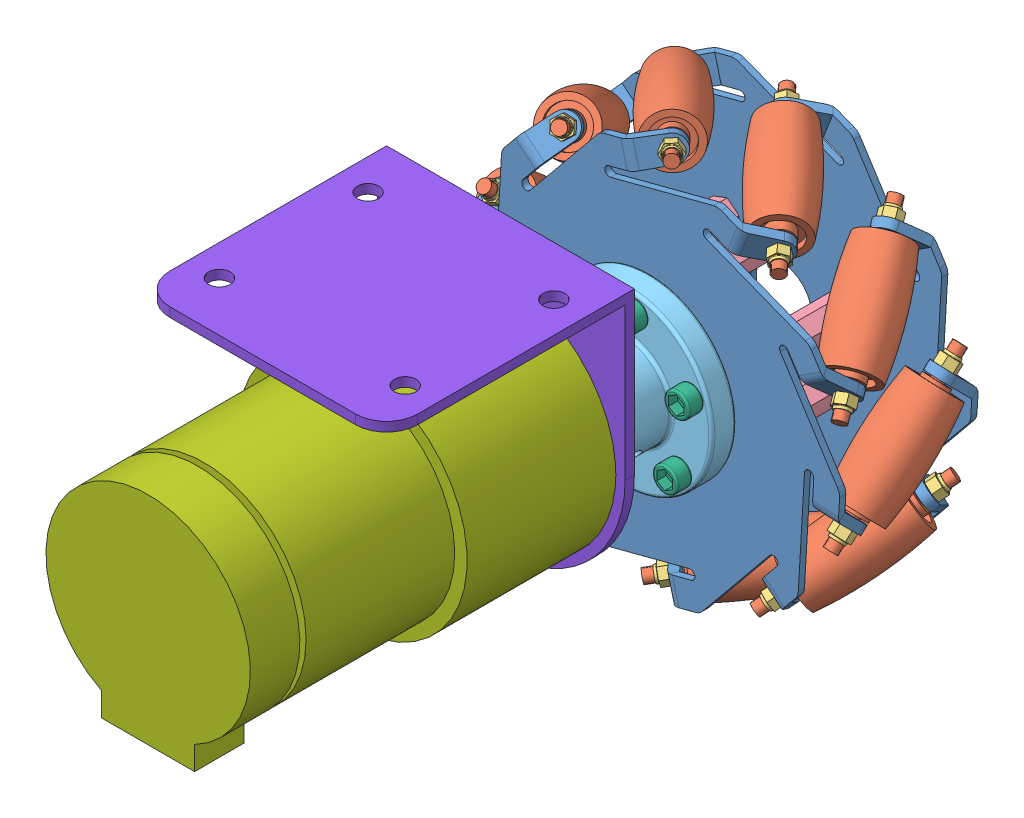
SolidWorks assembly 右后轮, configuration 默认. Lengths in mm.
Overall size (90.68 90.68 106.57).
61 component instances, 8 part files, 16 mates.
Components (placement in the parent):
- 麦克纳姆轮装配（2）-1: 麦克纳姆轮装配（2） [默认] at (-61.9802 -80.9379 78.6914) x (-0.633859 -0.773449 0) z (0 0 1) size (73.19 68.37 28.98)
  - 麦克纳姆轮（2）-1: 麦克纳姆轮（2） [默认] at (4.7846 1.1432 62.959) size (62.96 61.4 5.95)
  - 麦克纳姆轮（2）-2: 麦克纳姆轮（2） [默认] at (4.7846 1.1432 85.0986) x (-1 0 0) z (0 0 -1) size (62.96 61.4 5.95)
  - 辊子-1: 辊子 [默认] at (-6.5323 29.7426 62.712) x (0.707107 0 0.707107) z (-0.707107 0 0.707107) size (28 9.23 9.23)
  - 辊子-2: 辊子 [默认] at (-21.1917 17.6211 62.6991) x (0.572061 0.415627 0.707107) z (-0.707107 -0.186947 0.681946) size (28 9.23 9.23)
  - 辊子-3: 辊子 [默认] at (-25.9161 -0.7943 62.6991) x (0.218508 0.672499 0.707107) z (-0.650722 -0.439573 0.619142) size (28 9.23 9.23)
  - 辊子-4: 辊子 [默认] at (-25.9121 3.0685 85.3457) x (0.218508 -0.672499 -0.707107) z (0.395342 -0.60148 0.694209) size (28 9.23 9.23)
  - 辊子-6: 辊子 [默认] at (-21.1812 -15.3423 85.3457) x (0.572061 -0.415627 -0.707107) z (0.647393 -0.300533 0.700401) size (28 9.23 9.23)
  - 辊子-7: 辊子 [默认] at (-6.5323 -27.4561 85.3457) x (0.707107 0 -0.707107) z (0.705301 0.071414 0.705301) size (28 9.23 9.23)
  - 辊子-8: 辊子 [默认] at (12.4393 -28.646 85.3457) x (0.572061 0.415627 -0.707107) z (0.714443 0.170963 0.678486) size (28 9.23 9.23)
  - 辊子-9: 辊子 [默认] at (35.4853 3.0808 62.6991) x (-0.218508 -0.672499 0.707107) z (-0.954109 -0.00482 -0.29942) size (28 9.23 9.23)
  - 辊子-10: 辊子 [默认] at (28.4831 20.7562 62.6991) x (0.218508 -0.672499 0.707107) z (-0.771684 0.324444 0.547028) size (28 9.23 9.23)
  - 辊子-11: 辊子 [默认] at (12.4289 30.9401 62.6991) x (0.572061 -0.415627 0.707107) z (-0.689 0.22422 0.689206) size (28 9.23 9.23)
  - M2【螺母】-1: M2【螺母】 [默认] at (-5.0722 29.3326 82.6238) x (0.808299 -0.139279 -0.572061) z (-0.572061 -0.415627 -0.707107) size (2.79 3.22 1.95)
  - M2【螺母】-2: M2【螺母】 [默认] at (13.3795 29.7426 82.6238) x (0.572061 -0.587785 -0.572061) z (-0.707107 0 -0.707107) size (2.79 3.22 1.95)
  - M2【螺母】-3: M2【螺母】 [默认] at (28.5483 19.2286 82.6238) x (0.117316 -0.811778 -0.572061) z (-0.572061 0.415627 -0.707107) size (2.79 3.22 1.95)
  - M2【螺母】-4: M2【螺母】 [默认] at (34.6402 1.8066 82.6238) x (-0.38224 -0.725698 -0.572061) z (-0.218508 0.672499 -0.707107) size (2.79 3.22 1.95)
  - M2【螺母】-5: M2【螺母】 [默认] at (29.3282 -15.8687 82.6238) x (-0.735794 -0.362427 -0.572061) z (0.218508 0.672499 -0.707107) size (2.79 3.22 1.95)
  - M2【螺母】-6: M2【螺母】 [默认] at (14.6414 -27.0461 82.6238) x (-0.808299 0.139279 -0.572061) z (0.572061 0.415627 -0.707107) size (2.79 3.22 1.95)
  - M2【螺母】-7: M2【螺母】 [默认] at (-3.8104 -27.4561 82.6238) x (-0.572061 0.587785 -0.572061) z (0.707107 0 -0.707107) size (2.79 3.22 1.95)
  - M2【螺母】-8: M2【螺母】 [默认] at (-18.9791 -16.9422 82.6238) x (-0.117316 0.811778 -0.572061) z (0.572061 -0.415627 -0.707107) size (2.79 3.22 1.95)
  - M2【螺母】-9: M2【螺母】 [默认] at (-25.071 0.4798 82.6238) x (0.38224 0.725698 -0.572061) z (0.218508 -0.672499 -0.707107) size (2.79 3.22 1.95)
  - M2【螺母】-10: M2【螺母】 [默认] at (-19.759 18.1552 82.6238) x (0.735794 0.362427 -0.572061) z (-0.218508 -0.672499 -0.707107) size (2.79 3.22 1.95)
  - M2【螺母】-11: M2【螺母】 [默认] at (-19.759 -15.8687 65.4339) x (0.972031 0.086079 0.218508) z (-0.218508 0.672499 0.707107) size (2.79 3.22 1.95)
  - M2【螺母】-12: M2【螺母】 [默认] at (-5.0722 -27.0461 65.4339) x (0.735794 0.640985 0.218508) z (-0.572061 0.415627 0.707107) size (2.79 3.22 1.95)
  - M2【螺母】-13: M2【螺母】 [默认] at (13.3795 -27.4561 65.4339) x (0.218508 0.951057 0.218508) z (-0.707107 0 0.707107) size (2.79 3.22 1.95)
  - M2【螺母】-14: M2【螺母】 [默认] at (28.5483 -16.9422 65.4339) x (-0.38224 0.897857 0.218508) z (-0.572061 -0.415627 0.707107) size (2.79 3.22 1.95)
  - M2【螺母】-15: M2【螺母】 [默认] at (34.6402 0.4798 65.4339) x (-0.836986 0.501706 0.218508) z (-0.218508 -0.672499 0.707107) size (2.79 3.22 1.95)
  - M2【螺母】-16: M2【螺母】 [默认] at (29.3282 18.1552 65.4339) x (-0.972031 -0.086079 0.218508) z (0.218508 -0.672499 0.707107) size (2.79 3.22 1.95)
  - M2【螺母】-17: M2【螺母】 [默认] at (14.6414 29.3326 65.4339) x (-0.735794 -0.640985 0.218508) z (0.572061 -0.415627 0.707107) size (2.79 3.22 1.95)
  - M2【螺母】-18: M2【螺母】 [默认] at (-3.8104 29.7426 65.4339) x (-0.218508 -0.951057 0.218508) z (0.707107 0 0.707107) size (2.79 3.22 1.95)
  - M2【螺母】-19: M2【螺母】 [默认] at (-18.9791 19.2286 65.4339) x (0.38224 -0.897857 0.218508) z (0.572061 0.415627 0.707107) size (2.79 3.22 1.95)
  - M2【螺母】-20: M2【螺母】 [默认] at (-25.071 1.8066 65.4339) x (0.836986 -0.501706 0.218508) z (0.218508 0.672499 0.707107) size (2.79 3.22 1.95)
  - 20mm长-M3【六角铜柱】-1: 20mm长-M3【六角铜柱】 [默认] at (14.7439 -4.6068 64.0986) size (4.27 4.93 20)
  - 20mm长-M3【六角铜柱】-2: 20mm长-M3【六角铜柱】 [默认] at (4.7846 -10.3568 64.0986) x (0.5 -0.866025 0) z (0 0 1) size (4.27 4.93 20)
  - 20mm长-M3【六角铜柱】-3: 20mm长-M3【六角铜柱】 [默认] at (-5.1747 -4.6068 64.0986) x (-0.5 -0.866025 0) z (0 0 1) size (4.27 4.93 20)
  - 20mm长-M3【六角铜柱】-4: 20mm长-M3【六角铜柱】 [默认] at (-5.1747 6.8932 64.0986) x (-1 0 0) z (0 0 1) size (4.27 4.93 20)
  - 20mm长-M3【六角铜柱】-5: 20mm长-M3【六角铜柱】 [默认] at (4.7846 12.6432 64.0986) x (-0.5 0.866025 0) z (0 0 1) size (4.27 4.93 20)
  - 20mm长-M3【六角铜柱】-6: 20mm长-M3【六角铜柱】 [默认] at (14.7439 6.8932 64.0986) x (0.5 0.866025 0) z (0 0 1) size (4.27 4.93 20)
- 法兰联轴器-1: 法兰联轴器 [默认] at (-64.1287 -85.3632 163.79) x (-0.633859 -0.773449 0) z (0 0 1) size (28 28 16)
- M3-8【内六角螺丝】-1: M3-8【内六角螺丝】 [默认] at (-55.2341 -92.6526 159.79) size (4 4 10.5)
- M3-8【内六角螺丝】-2: M3-8【内六角螺丝】 [默认] at (-53.3686 -81.3049 159.79) x (0.5 0.866025 0) z (0 0 1) size (4 4 10.5)
- M3-8【内六角螺丝】-3: M3-8【内六角螺丝】 [默认] at (-62.2633 -74.0155 159.79) x (-0.5 0.866025 0) z (0 0 1) size (4 4 10.5)
- M3-8【内六角螺丝】-4: M3-8【内六角螺丝】 [默认] at (-73.0234 -78.0738 159.79) x (-1 0 0) z (0 0 1) size (4 4 10.5)
- M3-8【内六角螺丝】-5: M3-8【内六角螺丝】 [默认] at (-74.8888 -89.4215 159.79) x (-0.5 -0.866025 0) z (0 0 1) size (4 4 10.5)
- M3-8【内六角螺丝】-6: M3-8【内六角螺丝】 [默认] at (-65.9942 -96.7109 159.79) x (0.5 -0.866025 0) z (0 0 1) size (4 4 10.5)
- M3-8【内六角螺丝】-7: M3-8【内六角螺丝】 [默认] at (-55.2341 -92.6526 149.6504) x (-0.533553 0.845766 0) z (0 0 -1) size (4 4 10.5)
- M3-8【内六角螺丝】-8: M3-8【内六角螺丝】 [默认] at (-53.3686 -81.3049 149.6504) x (-0.999232 -0.039188 0) z (0 0 -1) size (4 4 10.5)
- M3-8【内六角螺丝】-9: M3-8【内六角螺丝】 [默认] at (-62.2633 -74.0155 149.6504) x (-0.465678 -0.884954 0) z (0 0 -1) size (4 4 10.5)
- M3-8【内六角螺丝】-10: M3-8【内六角螺丝】 [默认] at (-73.0234 -78.0738 149.6504) x (0.533553 -0.845766 0) z (0 0 -1) size (4 4 10.5)
- M3-8【内六角螺丝】-11: M3-8【内六角螺丝】 [默认] at (-74.8888 -89.4215 149.6504) x (0.999232 0.039188 0) z (0 0 -1) size (4 4 10.5)
- M3-8【内六角螺丝】-12: M3-8【内六角螺丝】 [默认] at (-65.9942 -96.7109 149.6504) x (0.465678 0.884954 0) z (0 0 -1) size (4 4 10.5)
- 电机总装-1: 电机总装 [默认] at (0 0 8.0749) size (40 46 75)
  - 减速比1：10【码盘减速电机】-1: 减速比1：10【码盘减速电机】 [默认] at (-64.1287 -78.3632 203.7151) x (1 0 0) z (0 0 -1) size (37 37 75)
  - 电机支架-2: 电机支架 [默认] at (-64.1287 -78.3632 179.7151) x (1 0 0) z (0 0 -1) size (40 46 40)
  - M3-8【内六角螺丝】-13: M3-8【内六角螺丝】 [默认] at (-56.3787 -64.9398 186.2151) x (-1 0 0) z (0 0 -1) size (4 4 10.5)
  - M3-8【内六角螺丝】-14: M3-8【内六角螺丝】 [默认] at (-71.8787 -64.9398 186.2151) x (-0.5 -0.866025 0) z (0 0 -1) size (4 4 10.5)
  - M3-8【内六角螺丝】-15: M3-8【内六角螺丝】 [默认] at (-79.6287 -78.3632 186.2151) x (0.5 -0.866025 0) z (0 0 -1) size (4 4 10.5)
  - M3-8【内六角螺丝】-16: M3-8【内六角螺丝】 [默认] at (-71.8787 -91.7866 186.2151) x (1 0 0) z (0 0 -1) size (4 4 10.5)
  - M3-8【内六角螺丝】-17: M3-8【内六角螺丝】 [默认] at (-56.3787 -91.7866 186.2151) x (0.5 0.866025 0) z (0 0 -1) size (4 4 10.5)
  - M3-8【内六角螺丝】-18: M3-8【内六角螺丝】 [默认] at (-48.6287 -78.3632 186.2151) x (-0.5 0.866025 0) z (0 0 -1) size (4 4 10.5)
Mates (geometry in assembly coordinates):
- 同心1: concentric: cylinder of ? through (-64.1287 -85.3632 155.7151) axis (0 0 -1) radius 5; cylinder of ? through (-64.1287 -85.3632 155.7151) axis (0 0 1) radius 3
- 同心2: concentric: cylinder of ? through (-55.2341 -92.6526 155.7151) axis (0 0 -1) radius 1.5; cylinder of ? through (-55.2341 -92.6526 159.7151) axis (0 0 -1) radius 1.5
- 重合1: coincident: plane of ? through (-44.2124 -101.6851 155.7151) normal (0 0 1); plane of ? through (-64.1287 -85.3632 155.7151) normal (0 0 -1)
- 同心3: concentric: cylinder of ? through (-55.2341 -92.6526 159.7151) axis (0 0 -1) radius 1.5; cylinder of ? through (-55.2341 -92.6526 159.7151) axis (0 0 -1) radius 1.5
- 重合2: coincident: plane of ? through (-64.1287 -85.3632 159.7151) normal (0 0 1); plane of ? through (-55.2341 -92.6526 159.7151) normal (0 0 -1)
- 同心4: concentric: cylinder of ? through (-55.2341 -92.6526 133.5755) axis (0 0 1) radius 1.5; cylinder of ? through (-55.2341 -92.6526 133.5755) axis (0 0 1) radius 1.5
- 重合3: coincident: plane of ? through (-44.2124 -101.6851 133.5755) normal (0 0 -1); plane of ? through (-55.2341 -92.6526 133.5755) normal (0 0 1)
- 同心5: concentric: cylinder of ? through (-64.1287 -85.3632 155.7151) axis (0 0 1) radius 3; cylinder of ? through (-64.1287 -85.3632 161.7151) axis (0 0 1) radius 3
- 距离1: distance = 2 mm: plane of ? through (-64.1287 -85.3632 171.7151) normal (0 0 1); plane of ? through (-64.1287 -85.3632 173.7151) normal (0 0 -1)
- 同心6: concentric: cylinder of ? through (-64.1287 -85.3632 173.7151) axis (0 0 1) radius 5; cylinder of ? through (-64.1287 -85.3632 178.2151) axis (0 0 1) radius 5
- 重合5: coincident: plane of ? through (-64.1287 -78.3632 179.7151) normal (0 0 -1); plane of ? through (-65.7369 -78.0377 179.7151) normal (0 0 1)
- 重合7: coincident: plane of ? through (-64.1287 -78.3632 179.7151) normal (0 0 -1); plane of ? through (-63.6111 -78.0508 179.7151) normal (0 0 1)
- 同心14: concentric: cylinder of ? through (-71.8787 -64.9398 184.7151) axis (0 0 -1) radius 1.5; cylinder of ? through (-71.8787 -64.9398 178.2151) axis (0 0 1) radius 1.5
- 同心15: concentric: cylinder of ? through (-56.3787 -64.9398 184.7151) axis (0 0 -1) radius 1.5; cylinder of ? through (-56.3787 -64.9398 178.2151) axis (0 0 1) radius 1.5
- 同心16: concentric: cylinder of ? through (-64.1287 -85.3632 155.7151) axis (0 0 1) radius 3; cylinder of 电机总装-1/减速比1：10【码盘减速电机】-1 through (-64.1287 -85.3632 169.79) axis (0 0 1) radius 3
- 距离2: distance = 2 mm: plane of 电机总装-1/减速比1：10【码盘减速电机】-1 through (-64.1287 -85.3632 181.79) normal (0 0 -1); plane of 法兰联轴器-1 through (-64.1287 -85.3632 179.79) normal (0 0 1)
